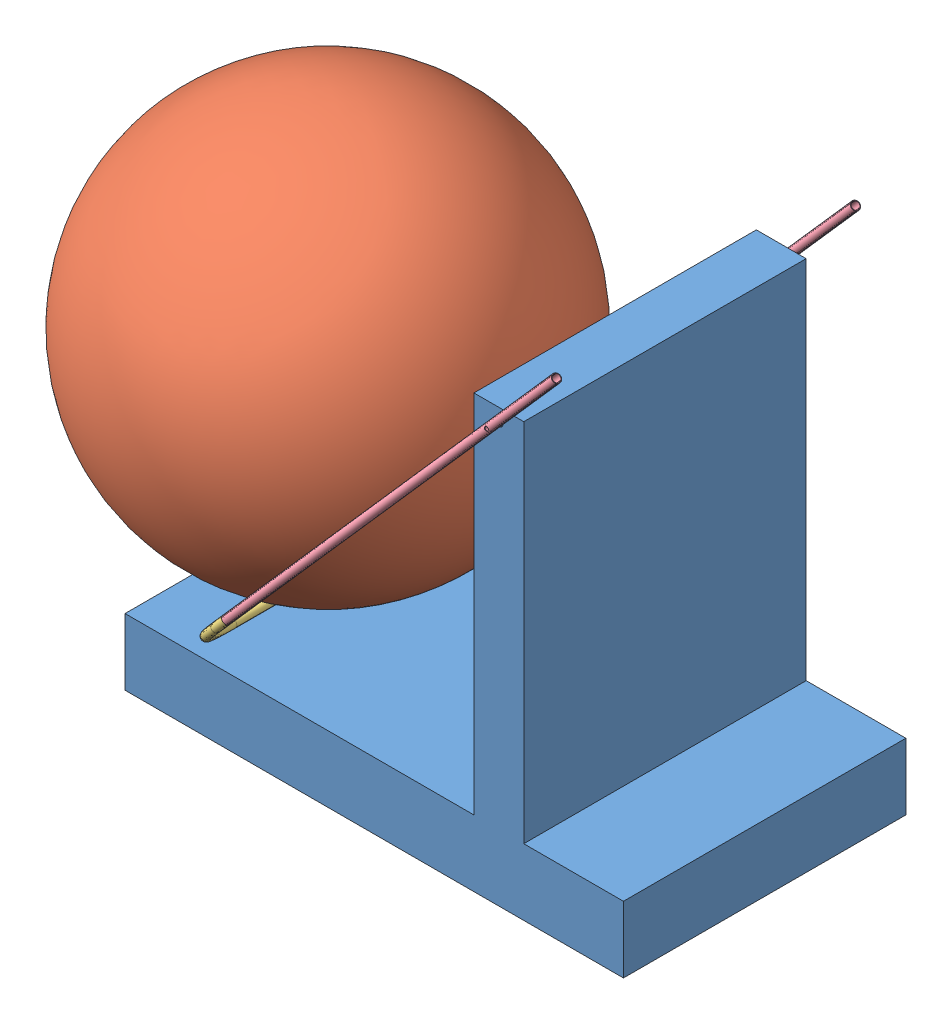
SolidWorks assembly Shooter Assembly, configuration Ready. Lengths in mm.
Overall size (1104.12 780.99 927.78).
5 component instances, 4 part files, 12 mates.
Components (placement in the parent):
- Robot Frame-1: Robot Frame [Default] at origin size (762 660.4 431.8)
- 2014 ball-1: 2014 ball [Default] at (-287.0227 368.2188 0) x (0.054809 -0.985809 -0.158669) z (0.529263 0.16343 -0.832569) size (609.6 609.6 609.6)
- Shooter End Bar-1: Shooter End Bar [Default] at (-279.9146 57.15 0) x (0 0 -1) z (0.75 -0.661438 0) size (469.9 107.95 12.7)
- Shooter Side bar-1: Shooter Side bar [Default] at (291.3031 704.85 -228.6) x (-0.661438 -0.75 0) z (0 0 -1) size (762 12.7 12.7)
- Shooter Side bar-2: Shooter Side bar [Default] at (291.3031 704.85 228.6) x (-0.661438 -0.75 0) z (0 0 -1) size (762 12.7 12.7)
Mates (geometry in assembly coordinates):
- Concentric1: concentric aligned: cylinder of Shooter End Bar-1 through (-229.513 114.3 228.6) axis (0.661438 0.75 0) radius 6.35; cylinder of Shooter Side bar-2 through (-212.7125 133.35 228.6) axis (0.661438 0.75 0) radius 6.35
- Coincident1: coincident anti-aligned: plane of Shooter End Bar-1 through (-212.7125 133.35 228.6) normal (0.661438 0.75 0); plane of Shooter Side bar-2 through (-212.7125 133.35 228.6) normal (-0.661438 -0.75 0)
- Concentric2: concentric aligned: cylinder of Shooter End Bar-1 through (-229.513 114.3 -228.6) axis (0.661438 0.75 0) radius 6.35; cylinder of Shooter Side bar-1 through (-212.7125 133.35 -228.6) axis (0.661438 0.75 0) radius 6.35
- Coincident2: coincident anti-aligned: plane of Shooter End Bar-1 through (-212.7125 133.35 -228.6) normal (0.661438 0.75 0); plane of Shooter Side bar-1 through (-212.7125 133.35 -228.6) normal (-0.661438 -0.75 0)
- Concentric3: concentric aligned: cylinder of Shooter Side bar-1 through (190.5 590.55 -222.25) axis (0 0 -1) radius 3.175; cylinder of Shooter Side bar-2 through (190.5 590.55 234.95) axis (0 0 -1) radius 3.175
- Concentric4: concentric anti-aligned: cylinder of Robot Frame-1 through (190.5 590.55 -215.9) axis (0 0 1) radius 6.35; cylinder of Shooter Side bar-1 through (190.5 590.55 -222.25) axis (0 0 -1) radius 3.175
- Coincident3: coincident anti-aligned: plane of Shooter End Bar-1; plane of assembly through (0 0 0) normal (0 0 1)
- Tangent1: tangent anti-aligned: sphere of 2014 ball-1; cylinder of Shooter End Bar-1 through (-279.9146 57.15 152.4) axis (0 0 -1) radius 6.35
- Tangent3: tangent anti-aligned: sphere of 2014 ball-1; cylinder of Shooter Side bar-1 through (-212.7125 133.35 -228.6) axis (0.661438 0.75 0) radius 6.35
- Tangent4: tangent anti-aligned: sphere of 2014 ball-1; cylinder of Shooter Side bar-2 through (-212.7125 133.35 228.6) axis (0.661438 0.75 0) radius 6.35
- Tangent5: tangent anti-aligned: plane of Robot Frame-1 through (0 50.8 215.9) normal (0 1 0); cylinder of Shooter End Bar-1 through (-279.9146 57.15 152.4) axis (0 0 -1) radius 6.35
- Coincident4: coincident: point of ?
